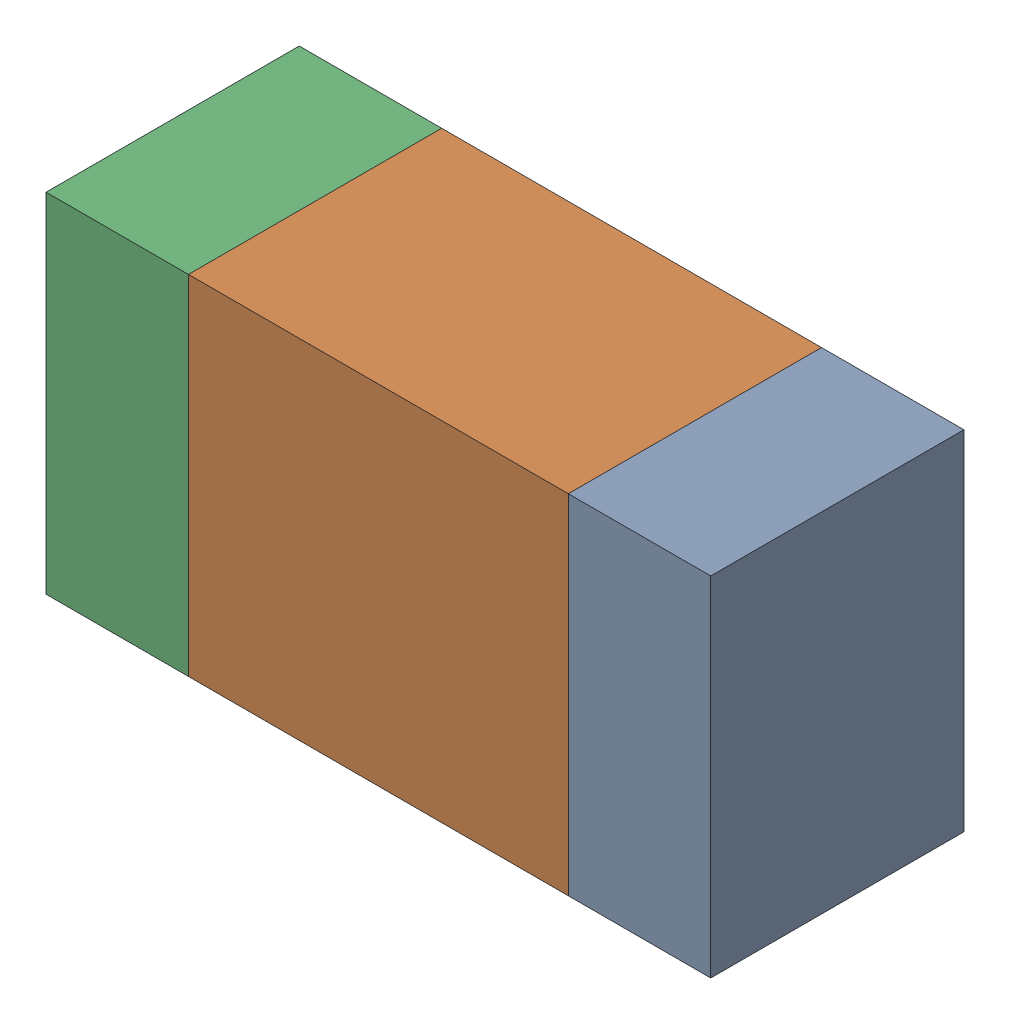
SolidWorks assembly R114_2PCB, configuration Default. Lengths in mm.
Overall size (1.05 0.55 0.4).
6 component instances, 2 part files, 0 mates.
Components (placement in the parent):
- 854785432-1: 854785432 [Default] at (112.8124 99.0999 0) size (0.22 0.55 0.4)
  - Extruded-1: Extruded [Default] at origin size (0.22 0.55 0.4)
- 854785568-1: 854785568 [Default] at (112.3999 99.0999 0) size (0.6 0.55 0.4)
  - Extruded_2-1: Extruded_2 [Default] at origin size (0.6 0.55 0.4)
- 854785432-2: 854785432 [Default] at (111.9874 99.0999 0) size (0.22 0.55 0.4)
  - Extruded-1: Extruded [Default] at origin size (0.22 0.55 0.4)
